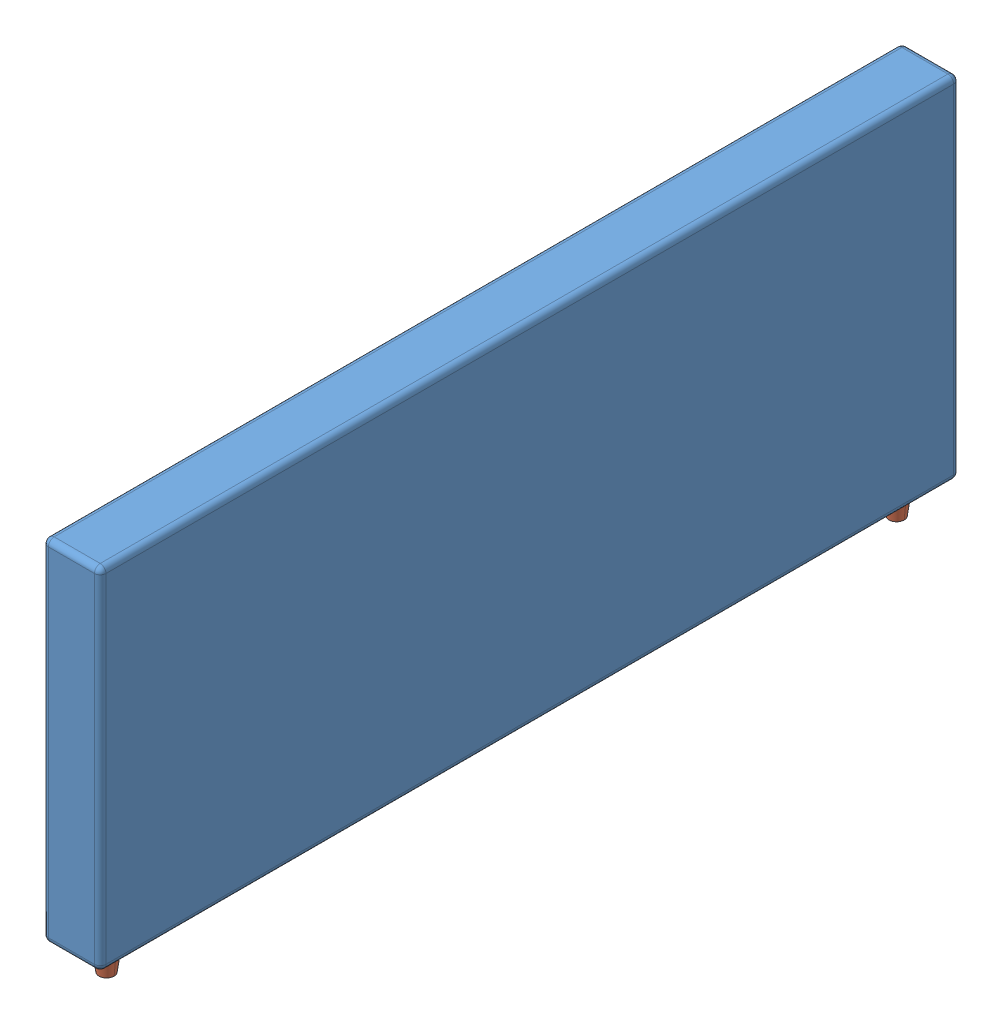
SolidWorks assembly Seitenwand-Lang, configuration Standard. Lengths in mm.
Overall size (104.2 660.82 1496.88).
3 component instances, 2 part files, 9 mates.
Components (placement in the parent):
- Seitenwand-Lang-1: Seitenwand-Lang [Standard] at (1050 -220 -1510) x (-1 0 0) z (0 1 0) size (104.2 1496.88 608.31)
- Standfuss-1: Standfuss [Standard] at (-60.9826 -218.2982 -1512.6869) x (-1 0 0) z (0 0.999999 0.001172) size (43.37 42.87 53.74)
- Standfuss-2: Standfuss [Standard] at (-60.9826 -218.2982 -2885.3529) x (-1 0 0) z (0 0.999999 0.001172) size (43.37 42.87 53.74)
Mates (geometry in assembly coordinates):
- Deckungsgleich1: coincident anti-aligned: plane of Seitenwand-Lang-1 through (118.5989 -608.1981 -1492.6859) normal (0 -1 0); plane of Standfuss-2 through (194.832 -608.1981 -1464.8045) normal (0 1 0)
- Deckungsgleich2: coincident anti-aligned: plane of Seitenwand-Lang-1 through (118.5989 -608.1981 -1492.6859) normal (0 -1 0); plane of Standfuss-1 through (194.832 -608.1981 -92.1385) normal (0 1 0)
- Abstand1: distance = 50 mm: line of Standfuss-2 through (-50 -660.0005 -1433.709) axis (0 0.999801 0.019937); line of Seitenwand-Lang-1 through (-90 -608.1981 -1482.6859) axis (1 0 0)
- Abstand2: distance = 40 mm: line of Standfuss-2 through (-50 -660.0005 -1433.709) axis (0 0.999801 0.019937); line of Seitenwand-Lang-1 through (-10 -608.1981 -1482.6859) axis (0 0 1)
- Abstand3: distance = 50 mm: line of Standfuss-1 through (-50 -660.0005 -61.0429) axis (0 0.999801 0.019937); line of Seitenwand-Lang-1 through (-10 -608.1981 -10) axis (-1 0 0)
- Abstand4: distance = 40 mm: line of Standfuss-1 through (-50 -660.0005 -61.0429) axis (0 0.999801 0.019937); line of Seitenwand-Lang-1 through (-10 -608.1981 -1482.6859) axis (0 0 1)
- Deckungsgleich7: coincident aligned: plane of Seitenwand-Lang-1 through (-100 0 -1492.6859) normal (0 1 0); plane of assembly
- Deckungsgleich8: coincident aligned: plane of Seitenwand-Lang-1 through (0 0 0) normal (0 0 1); plane of assembly
- Deckungsgleich9: coincident aligned: plane of Seitenwand-Lang-1 through (0 0 -1492.6859) normal (1 0 0); plane of assembly
